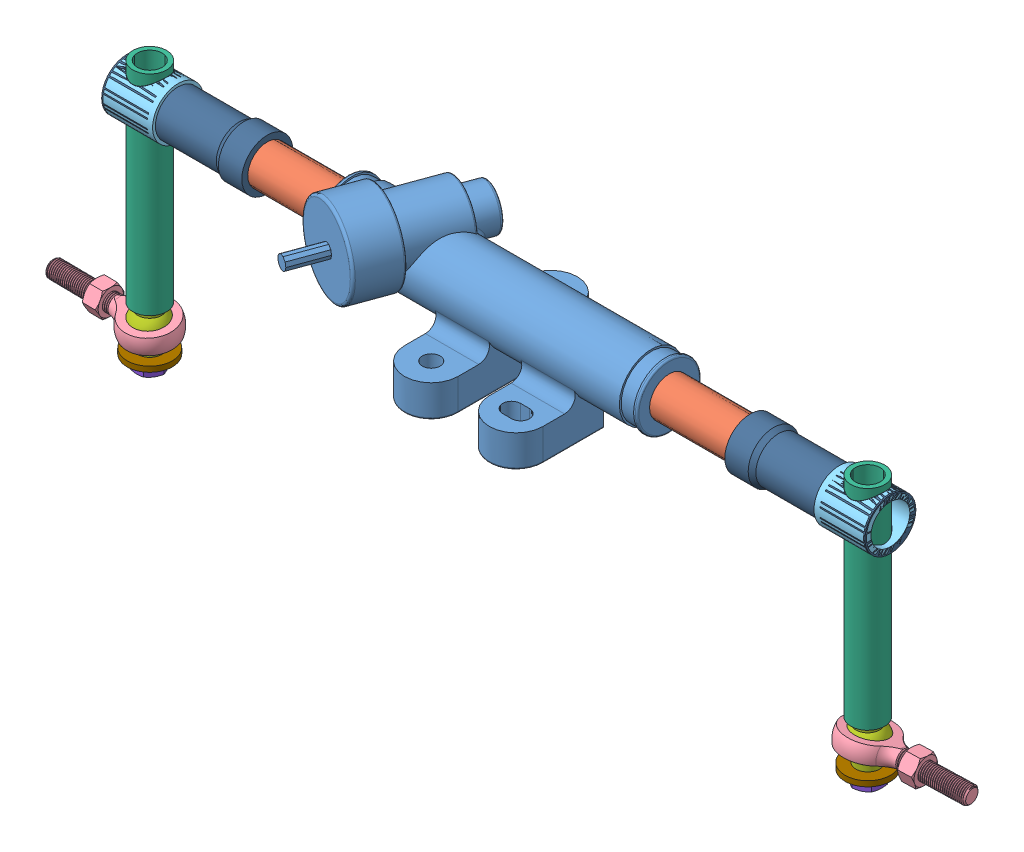
SolidWorks assembly steering assembly, configuration Default. Lengths in mm.
Overall size (513.18 167.92 106.9).
22 component instances, 12 part files, 36 mates.
Components (placement in the parent):
- prebuilt housing-1: prebuilt housing [Default] at (-22.0598 82.7728 134.0833) size (180 70.59 106.9)
- prebuilt rack-1: prebuilt rack [Default] at (207.9402 82.7728 134.0833) x (0 0.567124 0.823632) z (0 -0.823632 0.567124) size (22 312 22)
- extender-1: extender [Default] at (291.9402 82.7728 134.0833) x (0 0.924347 0.381554) z (0 -0.381554 0.924347) size (21.8 50.55 21.8)
- 3-8-24 swivel-3: 3-8-24 swivel [Default] at (-185.9718 28.0647 159.5712) x (-0.006612 0.105102 -0.994439) z (-0.023578 -0.994201 -0.10492) size (28.57 68.61 16.22)
- 3-8-24 swivel-4: 3-8-24 swivel [Default] at (322.7778 -82.9746 160.48) x (-0.097322 -0.214285 -0.971911) z (0.03722 0.97508 -0.21871) size (28.57 68.61 16.22)
- RackVertAdapt-1: RackVertAdapt [Default] at (-146.1968 82.7728 134.0833) size (28.57 28.57 28.57)
- RackVertAdapt-2: RackVertAdapt [Default] at (282.0773 82.7728 134.0833) x (-1 0 0) z (0 0 -1) size (28.57 28.57 28.57)
- Rackvertical-1: Rackvertical [Default] at (-133.4968 -16.996 134.0833) size (19.05 117.47 19.05)
- Rackvertical-2: Rackvertical [Default] at (269.3773 -16.996 134.0833) x (-0.951218 0 -0.308519) z (0.308519 0 -0.951218) size (19.05 117.47 19.05)
- BallSuper-Swivel  Joint Rod End6960T231_-1: BallSuper-Swivel  Joint Rod End6960T231_ [6960T231] at (-128.0548 -28.1085 115.8271) x (0.958328 0 0.28567) z (0 -1 0) size (20.64 20.64 22.23)
- BallSuper-Swivel  Joint Rod End6960T231_-2: BallSuper-Swivel  Joint Rod End6960T231_ [6960T231] at (287.2157 -28.1085 127.398) x (0.350934 0 0.9364) z (0 -1 0) size (20.64 20.64 22.23)
- 91257A659_Zinc Yellow-Chromate Plated Hex Head Screw-3: 91257A659_Zinc Yellow-Chromate Plated Hex Head Screw [91257A659] at (269.3773 -19.9805 134.0833) x (0 1 0) z (-0.577019 0 0.816731) size (57.6 16.5 14.29)
- 91257A659_Zinc Yellow-Chromate Plated Hex Head Screw-4: 91257A659_Zinc Yellow-Chromate Plated Hex Head Screw [91257A659] at (-133.4968 -19.9805 134.0833) x (0 1 0) z (-0.036356 0 0.999339) size (57.6 16.5 14.29)
- 3-8 98029A046_Black-Oxide Steel Oversized Washer-2: 3-8 98029A046_Black-Oxide Steel Oversized Washer [98029A046] at (-133.4968 -40.7133 134.0833) x (0.994656 0 -0.103243) z (0 1 0) size (25.4 25.4 2.98)
- 3-8 98029A046_Black-Oxide Steel Oversized Washer-3: 3-8 98029A046_Black-Oxide Steel Oversized Washer [98029A046] at (269.3773 -40.7133 134.0833) x (1 0 0) z (0 1 0) size (25.4 25.4 2.98)
- Part1^steering assembly-1: Part1^steering assembly [Default] at origin (virtual)
- GussetSteering-3: GussetSteering [Not Open] [Default] at (-96.2502 -463.7017 134.0833) x (0 -1 0) z (0 0 1) (suppressed, hidden)
- extender-3: extender [Default] at (-156.0598 82.7728 134.0833) x (0 -1 0) z (0 0 1) size (21.8 50.55 21.8)
- GussetSteering-4: GussetSteering [Not Open] [Default] at (252.5843 -463.7017 132.5593) x (0 -1 0) z (0 0 -1) (suppressed, hidden)
- GussetSteering-5: GussetSteering [Not Open] [Default] at (252.5843 -463.7017 132.5593) x (0 -1 0) z (0 0 -1) (suppressed, hidden)
- extender2-1: extender2 [Default] at (203.4389 82.7728 134.0833) size (78.98 28.57 28.57)
- extender2-2: extender2 [Default] at (-67.5584 82.7728 134.0833) x (-1 0 0) z (0 0 -1) size (78.98 28.57 28.57)
Mates (geometry in assembly coordinates):
- Concentric1: concentric anti-aligned: cylinder of prebuilt housing-1 through (157.9402 82.7728 134.0833) axis (-1 0 0) radius 11; cylinder of prebuilt rack-1 through (-72.0598 82.7728 134.0833) axis (1 0 0) radius 11
- Concentric8: concentric anti-aligned: circle of prebuilt rack-1; cylinder of extender-1 through (258.4802 82.7728 134.0833) axis (1 0 0) radius 10.9
- Concentric15: concentric aligned: cylinder of extender-1 through (258.4802 82.7728 134.0833) axis (1 0 0) radius 10.9; cylinder of RackVertAdapt-2 through (253.5023 82.7728 134.0833) axis (1 0 0) radius 10.9093
- Concentric19: concentric anti-aligned: circle of Rackvertical-1; circle of BallSuper-Swivel  Joint Rod End6960T231_-1
- Concentric22: concentric anti-aligned: circle of Rackvertical-2; circle of BallSuper-Swivel  Joint Rod End6960T231_-2
- Coincident16: coincident aligned: plane of Rackvertical-2 through (278.4376 -16.996 137.0219) normal (0 -1 0); circle of BallSuper-Swivel  Joint Rod End6960T231_-2
- Concentric23: concentric anti-aligned: circle of BallSuper-Swivel  Joint Rod End6960T231_-1; circle of 3-8 98029A046_Black-Oxide Steel Oversized Washer-2
- Coincident17: coincident anti-aligned: circle of BallSuper-Swivel  Joint Rod End6960T231_-1; plane of 3-8 98029A046_Black-Oxide Steel Oversized Washer-2 through (-133.4968 -39.221 134.0833) normal (0 1 0)
- Concentric25: concentric anti-aligned: circle of BallSuper-Swivel  Joint Rod End6960T231_-2; circle of 3-8 98029A046_Black-Oxide Steel Oversized Washer-3
- Coincident19: coincident anti-aligned: circle of BallSuper-Swivel  Joint Rod End6960T231_-2; plane of 3-8 98029A046_Black-Oxide Steel Oversized Washer-3 through (269.3773 -39.221 134.0833) normal (0 1 0)
- Coincident21: coincident aligned: plane of 91257A659_Zinc Yellow-Chromate Plated Hex Head Screw-3 through (261.8866 -42.2055 137.5379) normal (0 1 0); circle of 3-8 98029A046_Black-Oxide Steel Oversized Washer-3
- Concentric32: concentric anti-aligned: cylinder of 91257A659_Zinc Yellow-Chromate Plated Hex Head Screw-4 through (-133.4968 -42.2055 134.0833) axis (0 1 0) radius 4.7625; cylinder of 3-8 98029A046_Black-Oxide Steel Oversized Washer-2 through (-133.4968 -39.221 134.0833) axis (0 -1 0) radius 5.1562
- Coincident34: coincident: moEndPointRef_w of 91257A659_Zinc Yellow-Chromate Plated Hex Head Screw-4; plane of 3-8 98029A046_Black-Oxide Steel Oversized Washer-2 through (-133.4968 -42.2055 134.0833) normal (0 -1 0)
- Lock4: lock: unknown of RackVertAdapt-1; unknown of Rackvertical-1
- Lock6: lock: unknown of prebuilt rack-1; unknown of extender-1
- Lock7: lock: unknown of extender-1; unknown of RackVertAdapt-2
- Lock8: lock: unknown of RackVertAdapt-2; unknown of Rackvertical-2
- Lock9: lock: unknown of Rackvertical-2; unknown of BallSuper-Swivel  Joint Rod End6960T231_-2
- Concentric35: concentric anti-aligned: cylinder of 91257A659_Zinc Yellow-Chromate Plated Hex Head Screw-3 through (269.3773 -42.2055 134.0833) axis (0 1 0) radius 4.7625; cylinder of 3-8 98029A046_Black-Oxide Steel Oversized Washer-3 through (269.3773 -39.221 134.0833) axis (0 -1 0) radius 12.7
- Coincident54: coincident: point of 3-8-24 swivel-3; point of BallSuper-Swivel  Joint Rod End6960T231_-1
- Coincident56: coincident: point of 3-8-24 swivel-4; point of BallSuper-Swivel  Joint Rod End6960T231_-2
- Parallel1: parallel: line of Rackvertical-2 through (269.3773 100.479 134.0833) axis (0 -1 0)
- Coincident58: coincident aligned: plane of Rackvertical-1 through (-143.0218 -16.996 134.0833) normal (0 -1 0); circle of BallSuper-Swivel  Joint Rod End6960T231_-1
- Coincident73: coincident anti-aligned: plane of prebuilt rack-1 through (-72.0598 95.1403 107.9625) normal (-1 0 0); plane of extender-3 through (-72.0598 82.7728 134.0833) normal (1 0 0)
- Concentric36: concentric aligned: cylinder of prebuilt rack-1 through (-72.0598 82.7728 134.0833) axis (1 0 0) radius 11; cylinder of extender-3 through (-122.5998 82.7728 134.0833) axis (1 0 0) radius 10.9
- Concentric37: concentric anti-aligned: cylinder of RackVertAdapt-1 through (-117.6218 82.7728 134.0833) axis (-1 0 0) radius 14.2875; cylinder of extender-3 through (-122.5998 82.7728 134.0833) axis (1 0 0) radius 10.9
- Lock16: lock: unknown of RackVertAdapt-1; unknown of extender-3
- Lock19: lock: unknown of prebuilt rack-1; unknown of extender-3
- Parallel2: parallel aligned: line of Rackvertical-1 through (-133.4968 100.479 134.0833) axis (0 -1 0); line of Rackvertical-2 through (269.3773 100.479 134.0833) axis (0 -1 0)
- Perpendicular1: perpendicular: plane of prebuilt housing-1 through (57.9402 48.7728 100.5833) normal (0 -1 0); line of Rackvertical-1 through (-133.4968 100.479 134.0833) axis (0 -1 0)
- Coincident76: coincident: point of prebuilt rack-1; point of assembly
- Concentric39: concentric anti-aligned: line of Rackvertical-2 through (269.3773 100.479 134.0833) axis (0 -1 0); cylinder of extender2-1 through (269.3773 57.3728 134.0833) axis (0 1 0) radius 9.525
- Concentric38: concentric anti-aligned: cylinder of prebuilt rack-1 through (-72.0598 82.7728 134.0833) axis (1 0 0) radius 11; cylinder of extender2-1 through (203.4389 82.7728 134.0833) axis (-1 0 0) radius 14.2875
- Coincident78: coincident: point of prebuilt rack-1; point of assembly
- Concentric40: concentric anti-aligned: line of Rackvertical-1 through (-133.4968 100.479 134.0833) axis (0 -1 0); cylinder of extender2-2 through (-133.4968 57.3728 134.0833) axis (0 1 0) radius 9.525
- Concentric41: concentric aligned: cylinder of prebuilt rack-1 through (-72.0598 82.7728 134.0833) axis (1 0 0) radius 11; cylinder of extender2-2 through (-67.5584 82.7728 134.0833) axis (1 0 0) radius 14.2875
